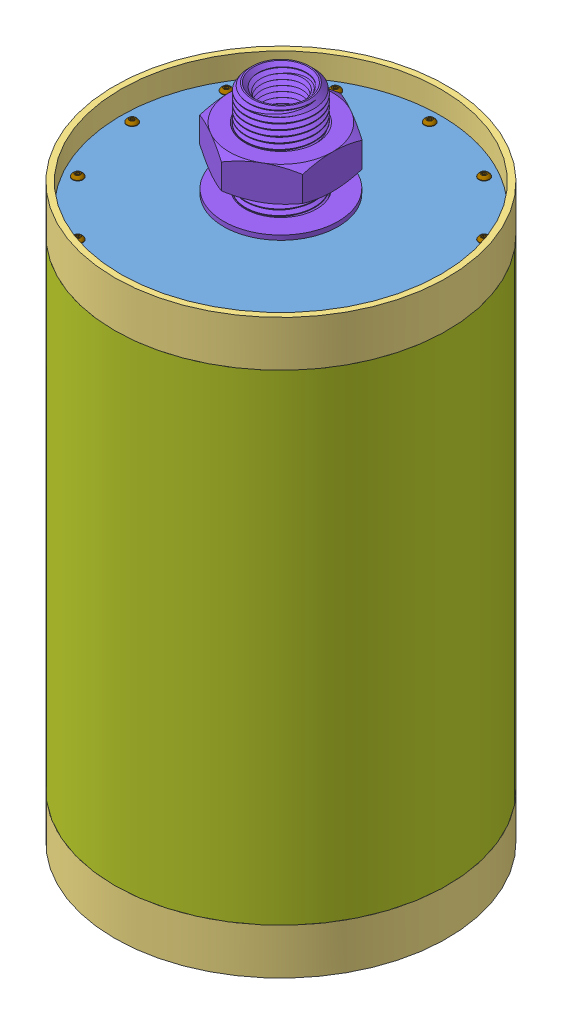
SolidWorks assembly Cryo Tank, configuration Default. Lengths in mm.
Overall size (92.25 182.79 92.25).
59 component instances, 10 part files, 35 mates.
Components (placement in the parent):
- End Cap-1: End Cap [Default] at origin size (88.9 3.17 88.9)
- Liner-1: Liner [Default] at (0 -4.7625 0) size (77.77 133.35 77.77)
- Main Ring-1: Main Ring [Default] at (0 -1.5875 0) size (92.25 25.4 92.25)
- Ring Seal-1: Ring Seal [Default] at (0 -1.5875 0) size (88.9 1.59 88.9)
- Main Ring-2: Main Ring [Default] at (0 -141.2875 0) x (-1 0 0) z (0 0 1) size (92.25 25.4 92.25)
- Ring Seal-2: Ring Seal [Default] at (0 -142.875 0) size (88.9 1.59 88.9)
- End Cap-2: End Cap [Default] at (0 -142.875 0) x (-1 0 0) z (0 0 1) size (88.9 3.17 88.9)
- 90273A015_ZINC-PLATED STL FLAT HEAD PHIL MACHINE SCREW-1: 90273A015_ZINC-PLATED STL FLAT HEAD PHIL MACHINE SCREW [90273A015] at (-35.7452 0.6985 20.6375) x (1 0 0) z (0 1 0) size (2.84 2.84 8.46) (hidden)
- 90273A015_ZINC-PLATED STL FLAT HEAD PHIL MACHINE SCREW-2: 90273A015_ZINC-PLATED STL FLAT HEAD PHIL MACHINE SCREW [90273A015] at (-41.275 0.6985 0) x (0.866025 0 0.5) z (0 1 0) size (2.84 2.84 8.46) (hidden)
- 90273A015_ZINC-PLATED STL FLAT HEAD PHIL MACHINE SCREW-3: 90273A015_ZINC-PLATED STL FLAT HEAD PHIL MACHINE SCREW [90273A015] at (-35.7452 0.6985 -20.6375) x (0.5 0 0.866025) z (0 1 0) size (2.84 2.84 8.46) (hidden)
- 90273A015_ZINC-PLATED STL FLAT HEAD PHIL MACHINE SCREW-4: 90273A015_ZINC-PLATED STL FLAT HEAD PHIL MACHINE SCREW [90273A015] at (-20.6375 0.6985 -35.7452) x (0 0 1) z (0 1 0) size (2.84 2.84 8.46) (hidden)
- 90273A015_ZINC-PLATED STL FLAT HEAD PHIL MACHINE SCREW-5: 90273A015_ZINC-PLATED STL FLAT HEAD PHIL MACHINE SCREW [90273A015] at (0 0.6985 -41.275) x (-0.5 0 0.866025) z (0 1 0) size (2.84 2.84 8.46) (hidden)
- 90273A015_ZINC-PLATED STL FLAT HEAD PHIL MACHINE SCREW-6: 90273A015_ZINC-PLATED STL FLAT HEAD PHIL MACHINE SCREW [90273A015] at (20.6375 0.6985 -35.7452) x (-0.866025 0 0.5) z (0 1 0) size (2.84 2.84 8.46) (hidden)
- 90273A015_ZINC-PLATED STL FLAT HEAD PHIL MACHINE SCREW-7: 90273A015_ZINC-PLATED STL FLAT HEAD PHIL MACHINE SCREW [90273A015] at (35.7452 0.6985 -20.6375) x (-1 0 0) z (0 1 0) size (2.84 2.84 8.46) (hidden)
- 90273A015_ZINC-PLATED STL FLAT HEAD PHIL MACHINE SCREW-8: 90273A015_ZINC-PLATED STL FLAT HEAD PHIL MACHINE SCREW [90273A015] at (41.275 0.6985 0) x (-0.866025 0 -0.5) z (0 1 0) size (2.84 2.84 8.46) (hidden)
- 90273A015_ZINC-PLATED STL FLAT HEAD PHIL MACHINE SCREW-9: 90273A015_ZINC-PLATED STL FLAT HEAD PHIL MACHINE SCREW [90273A015] at (35.7452 0.6985 20.6375) x (-0.5 0 -0.866025) z (0 1 0) size (2.84 2.84 8.46) (hidden)
- 90273A015_ZINC-PLATED STL FLAT HEAD PHIL MACHINE SCREW-10: 90273A015_ZINC-PLATED STL FLAT HEAD PHIL MACHINE SCREW [90273A015] at (20.6375 0.6985 35.7452) x (0 0 -1) z (0 1 0) size (2.84 2.84 8.46) (hidden)
- 90273A015_ZINC-PLATED STL FLAT HEAD PHIL MACHINE SCREW-11: 90273A015_ZINC-PLATED STL FLAT HEAD PHIL MACHINE SCREW [90273A015] at (0 0.6985 41.275) x (0.5 0 -0.866025) z (0 1 0) size (2.84 2.84 8.46) (hidden)
- 90273A015_ZINC-PLATED STL FLAT HEAD PHIL MACHINE SCREW-12: 90273A015_ZINC-PLATED STL FLAT HEAD PHIL MACHINE SCREW [90273A015] at (-20.6375 0.6985 35.7452) x (0.866025 0 -0.5) z (0 1 0) size (2.84 2.84 8.46) (hidden)
- 90273A015_ZINC-PLATED STL FLAT HEAD PHIL MACHINE SCREW-13: 90273A015_ZINC-PLATED STL FLAT HEAD PHIL MACHINE SCREW [90273A015] at (0 -143.5735 41.275) x (1 0 0) z (0 -1 0) size (2.84 2.84 8.46) (hidden)
- 90273A015_ZINC-PLATED STL FLAT HEAD PHIL MACHINE SCREW-25: 90273A015_ZINC-PLATED STL FLAT HEAD PHIL MACHINE SCREW [90273A015] at (-20.6375 -143.5735 35.7452) x (0.866025 0 0.5) z (0 -1 0) size (2.84 2.84 8.46) (hidden)
- 90273A015_ZINC-PLATED STL FLAT HEAD PHIL MACHINE SCREW-26: 90273A015_ZINC-PLATED STL FLAT HEAD PHIL MACHINE SCREW [90273A015] at (-35.7452 -143.5735 20.6375) x (0.5 0 0.866025) z (0 -1 0) size (2.84 2.84 8.46) (hidden)
- 90273A015_ZINC-PLATED STL FLAT HEAD PHIL MACHINE SCREW-27: 90273A015_ZINC-PLATED STL FLAT HEAD PHIL MACHINE SCREW [90273A015] at (-41.275 -143.5735 0) x (0 0 1) z (0 -1 0) size (2.84 2.84 8.46) (hidden)
- 90273A015_ZINC-PLATED STL FLAT HEAD PHIL MACHINE SCREW-28: 90273A015_ZINC-PLATED STL FLAT HEAD PHIL MACHINE SCREW [90273A015] at (-35.7452 -143.5735 -20.6375) x (-0.5 0 0.866025) z (0 -1 0) size (2.84 2.84 8.46) (hidden)
- 90273A015_ZINC-PLATED STL FLAT HEAD PHIL MACHINE SCREW-29: 90273A015_ZINC-PLATED STL FLAT HEAD PHIL MACHINE SCREW [90273A015] at (-20.6375 -143.5735 -35.7452) x (-0.866025 0 0.5) z (0 -1 0) size (2.84 2.84 8.46) (hidden)
- 90273A015_ZINC-PLATED STL FLAT HEAD PHIL MACHINE SCREW-30: 90273A015_ZINC-PLATED STL FLAT HEAD PHIL MACHINE SCREW [90273A015] at (0 -143.5735 -41.275) x (-1 0 0) z (0 -1 0) size (2.84 2.84 8.46) (hidden)
- 90273A015_ZINC-PLATED STL FLAT HEAD PHIL MACHINE SCREW-31: 90273A015_ZINC-PLATED STL FLAT HEAD PHIL MACHINE SCREW [90273A015] at (20.6375 -143.5735 -35.7452) x (-0.866025 0 -0.5) z (0 -1 0) size (2.84 2.84 8.46) (hidden)
- 90273A015_ZINC-PLATED STL FLAT HEAD PHIL MACHINE SCREW-32: 90273A015_ZINC-PLATED STL FLAT HEAD PHIL MACHINE SCREW [90273A015] at (35.7452 -143.5735 -20.6375) x (-0.5 0 -0.866025) z (0 -1 0) size (2.84 2.84 8.46) (hidden)
- 90273A015_ZINC-PLATED STL FLAT HEAD PHIL MACHINE SCREW-33: 90273A015_ZINC-PLATED STL FLAT HEAD PHIL MACHINE SCREW [90273A015] at (41.275 -143.5735 0) x (0 0 -1) z (0 -1 0) size (2.84 2.84 8.46) (hidden)
- 90273A015_ZINC-PLATED STL FLAT HEAD PHIL MACHINE SCREW-34: 90273A015_ZINC-PLATED STL FLAT HEAD PHIL MACHINE SCREW [90273A015] at (35.7452 -143.5735 20.6375) x (0.5 0 -0.866025) z (0 -1 0) size (2.84 2.84 8.46) (hidden)
- 90273A015_ZINC-PLATED STL FLAT HEAD PHIL MACHINE SCREW-35: 90273A015_ZINC-PLATED STL FLAT HEAD PHIL MACHINE SCREW [90273A015] at (20.6375 -143.5735 35.7452) x (0.866025 0 -0.5) z (0 -1 0) size (2.84 2.84 8.46) (hidden)
- CF Inner Layer-1: CF Inner Layer [Default] at (0 64.2407 0) size (79.04 133.35 79.04)
- Honeycomb Core-1: Honeycomb Core [Default] at (0 -50.3801 0) size (91.74 133.35 91.74)
- CF Outer Layer-1: CF Outer Layer [Default] at (0 15.1434 0) size (92.25 133.35 92.25)
- 50785K273_MED-PRESSURE BRASS THREADED PIPE FITTING-1: 50785K273_MED-PRESSURE BRASS THREADED PIPE FITTING [50785K273] at (0 12.7 0) x (1 0 0) z (0 -1 0) size (31.75 33 38.33)
- 98164A422_TYPE 316 SS BUTTON-HEAD SOCKET CAP SCREW-1: 98164A422_TYPE 316 SS BUTTON-HEAD SOCKET CAP SCREW [98164A422] at (-35.7452 2.4003 20.6375) x (1 0 0) z (0 1 0) size (2.9 2.9 7.34)
- 98164A422_TYPE 316 SS BUTTON-HEAD SOCKET CAP SCREW-2: 98164A422_TYPE 316 SS BUTTON-HEAD SOCKET CAP SCREW [98164A422] at (-41.275 2.4003 0) x (0.866025 0 0.5) z (0 1 0) size (2.9 2.9 7.34)
- 98164A422_TYPE 316 SS BUTTON-HEAD SOCKET CAP SCREW-3: 98164A422_TYPE 316 SS BUTTON-HEAD SOCKET CAP SCREW [98164A422] at (-35.7452 2.4003 -20.6375) x (0.5 0 0.866025) z (0 1 0) size (2.9 2.9 7.34)
- 98164A422_TYPE 316 SS BUTTON-HEAD SOCKET CAP SCREW-4: 98164A422_TYPE 316 SS BUTTON-HEAD SOCKET CAP SCREW [98164A422] at (-20.6375 2.4003 -35.7452) x (0 0 1) z (0 1 0) size (2.9 2.9 7.34)
- 98164A422_TYPE 316 SS BUTTON-HEAD SOCKET CAP SCREW-5: 98164A422_TYPE 316 SS BUTTON-HEAD SOCKET CAP SCREW [98164A422] at (0 2.4003 -41.275) x (-0.5 0 0.866025) z (0 1 0) size (2.9 2.9 7.34)
- 98164A422_TYPE 316 SS BUTTON-HEAD SOCKET CAP SCREW-6: 98164A422_TYPE 316 SS BUTTON-HEAD SOCKET CAP SCREW [98164A422] at (20.6375 2.4003 -35.7452) x (-0.866025 0 0.5) z (0 1 0) size (2.9 2.9 7.34)
- 98164A422_TYPE 316 SS BUTTON-HEAD SOCKET CAP SCREW-7: 98164A422_TYPE 316 SS BUTTON-HEAD SOCKET CAP SCREW [98164A422] at (35.7452 2.4003 -20.6375) x (-1 0 0) z (0 1 0) size (2.9 2.9 7.34)
- 98164A422_TYPE 316 SS BUTTON-HEAD SOCKET CAP SCREW-8: 98164A422_TYPE 316 SS BUTTON-HEAD SOCKET CAP SCREW [98164A422] at (41.275 2.4003 0) x (-0.866025 0 -0.5) z (0 1 0) size (2.9 2.9 7.34)
- 98164A422_TYPE 316 SS BUTTON-HEAD SOCKET CAP SCREW-9: 98164A422_TYPE 316 SS BUTTON-HEAD SOCKET CAP SCREW [98164A422] at (35.7452 2.4003 20.6375) x (-0.5 0 -0.866025) z (0 1 0) size (2.9 2.9 7.34)
- 98164A422_TYPE 316 SS BUTTON-HEAD SOCKET CAP SCREW-10: 98164A422_TYPE 316 SS BUTTON-HEAD SOCKET CAP SCREW [98164A422] at (20.6375 2.4003 35.7452) x (0 0 -1) z (0 1 0) size (2.9 2.9 7.34)
- 98164A422_TYPE 316 SS BUTTON-HEAD SOCKET CAP SCREW-11: 98164A422_TYPE 316 SS BUTTON-HEAD SOCKET CAP SCREW [98164A422] at (0 2.4003 41.275) x (0.5 0 -0.866025) z (0 1 0) size (2.9 2.9 7.34)
- 98164A422_TYPE 316 SS BUTTON-HEAD SOCKET CAP SCREW-12: 98164A422_TYPE 316 SS BUTTON-HEAD SOCKET CAP SCREW [98164A422] at (-20.6375 2.4003 35.7452) x (0.866025 0 -0.5) z (0 1 0) size (2.9 2.9 7.34)
- 98164A422_TYPE 316 SS BUTTON-HEAD SOCKET CAP SCREW-13: 98164A422_TYPE 316 SS BUTTON-HEAD SOCKET CAP SCREW [98164A422] at (0 -145.2753 41.275) x (1 0 0) z (0 -1 0) size (2.9 2.9 7.34)
- 98164A422_TYPE 316 SS BUTTON-HEAD SOCKET CAP SCREW-14: 98164A422_TYPE 316 SS BUTTON-HEAD SOCKET CAP SCREW [98164A422] at (-20.6375 -145.2753 35.7452) x (0.866025 0 0.5) z (0 -1 0) size (2.9 2.9 7.34)
- 98164A422_TYPE 316 SS BUTTON-HEAD SOCKET CAP SCREW-15: 98164A422_TYPE 316 SS BUTTON-HEAD SOCKET CAP SCREW [98164A422] at (-35.7452 -145.2753 20.6375) x (0.5 0 0.866025) z (0 -1 0) size (2.9 2.9 7.34)
- 98164A422_TYPE 316 SS BUTTON-HEAD SOCKET CAP SCREW-16: 98164A422_TYPE 316 SS BUTTON-HEAD SOCKET CAP SCREW [98164A422] at (-41.275 -145.2753 0) x (0 0 1) z (0 -1 0) size (2.9 2.9 7.34)
- 98164A422_TYPE 316 SS BUTTON-HEAD SOCKET CAP SCREW-17: 98164A422_TYPE 316 SS BUTTON-HEAD SOCKET CAP SCREW [98164A422] at (-35.7452 -145.2753 -20.6375) x (-0.5 0 0.866025) z (0 -1 0) size (2.9 2.9 7.34)
- 98164A422_TYPE 316 SS BUTTON-HEAD SOCKET CAP SCREW-18: 98164A422_TYPE 316 SS BUTTON-HEAD SOCKET CAP SCREW [98164A422] at (-20.6375 -145.2753 -35.7452) x (-0.866025 0 0.5) z (0 -1 0) size (2.9 2.9 7.34)
- 98164A422_TYPE 316 SS BUTTON-HEAD SOCKET CAP SCREW-19: 98164A422_TYPE 316 SS BUTTON-HEAD SOCKET CAP SCREW [98164A422] at (0 -145.2753 -41.275) x (-1 0 0) z (0 -1 0) size (2.9 2.9 7.34)
- 98164A422_TYPE 316 SS BUTTON-HEAD SOCKET CAP SCREW-20: 98164A422_TYPE 316 SS BUTTON-HEAD SOCKET CAP SCREW [98164A422] at (20.6375 -145.2753 -35.7452) x (-0.866025 0 -0.5) z (0 -1 0) size (2.9 2.9 7.34)
- 98164A422_TYPE 316 SS BUTTON-HEAD SOCKET CAP SCREW-21: 98164A422_TYPE 316 SS BUTTON-HEAD SOCKET CAP SCREW [98164A422] at (35.7452 -145.2753 -20.6375) x (-0.5 0 -0.866025) z (0 -1 0) size (2.9 2.9 7.34)
- 98164A422_TYPE 316 SS BUTTON-HEAD SOCKET CAP SCREW-22: 98164A422_TYPE 316 SS BUTTON-HEAD SOCKET CAP SCREW [98164A422] at (41.275 -145.2753 0) x (0 0 -1) z (0 -1 0) size (2.9 2.9 7.34)
- 98164A422_TYPE 316 SS BUTTON-HEAD SOCKET CAP SCREW-23: 98164A422_TYPE 316 SS BUTTON-HEAD SOCKET CAP SCREW [98164A422] at (35.7452 -145.2753 20.6375) x (0.5 0 -0.866025) z (0 -1 0) size (2.9 2.9 7.34)
- 98164A422_TYPE 316 SS BUTTON-HEAD SOCKET CAP SCREW-24: 98164A422_TYPE 316 SS BUTTON-HEAD SOCKET CAP SCREW [98164A422] at (20.6375 -145.2753 35.7452) x (0.866025 0 -0.5) z (0 -1 0) size (2.9 2.9 7.34)
Mates (geometry in assembly coordinates):
- Coincident13: coincident: point of Liner-1; point of assembly
- Coincident14: coincident aligned: plane of Liner-1 through (0 -4.7625 0) normal (0 0 1); plane of assembly through (0 0 0) normal (0 0 1)
- Coincident15: coincident aligned: plane of End Cap-1 through (0 0 0) normal (0 0 1); plane of assembly through (0 0 0) normal (0 0 1)
- Coincident16: coordinate: point of End Cap-1; point of assembly
- Coincident17: coincident anti-aligned: line of ? through (110 0 53.4125) axis (0 0 -1)
- Coincident18: coincident aligned: plane of Ring Seal-1 through (0 -1.5875 0) normal (0 0 1); plane of assembly through (0 0 0) normal (0 0 1)
- Coincident20: coincident anti-aligned: line of ? through (110 0 53.4125) axis (0 0 -1)
- Coincident21: coincident aligned: plane of Main Ring-1 through (0 -1.5875 0) normal (0 0 1); plane of assembly through (0 0 0) normal (0 0 1)
- Coincident22: coincident: unknown of ?
- Coincident23: coincident anti-aligned: line of Ring Seal-2 through (110 0 -87.875) axis (0 0 -1); line of assembly
- Coincident24: coincident aligned: plane of Ring Seal-2 through (0 -142.875 0) normal (0 0 1); plane of assembly through (0 0 0) normal (0 0 1)
- Coincident25: coincident: point of Ring Seal-2; point of assembly
- Coincident26: coincident aligned: line of End Cap-2 through (110 0 -197.875) axis (0 0 1); line of assembly
- Coincident27: coincident aligned: plane of End Cap-2 through (0 -142.875 0) normal (0 0 1); plane of assembly through (0 0 0) normal (0 0 1)
- Coincident28: coincident: point of End Cap-2; point of assembly
- Coincident29: coincident aligned: line of Main Ring-2 through (110 0 -196.2875) axis (0 0 1); line of assembly
- Coincident30: coincident aligned: plane of Main Ring-2 through (0 -141.2875 0) normal (0 0 1); plane of assembly through (0 0 0) normal (0 0 1)
- Coincident31: coincident: point of Main Ring-2; point of assembly
- Coincident32: coincident: unknown of ?
- Coincident33: coincident aligned: plane of End Cap-1 through (-44.45 1.5875 0) normal (0 1 0); plane of 90273A015_ZINC-PLATED STL FLAT HEAD PHIL MACHINE SCREW-1 through (-35.7452 1.5875 19.8755) normal (0 1 0)
- Concentric1: concentric anti-aligned: circle of End Cap-1; circle of 90273A015_ZINC-PLATED STL FLAT HEAD PHIL MACHINE SCREW-1
- Concentric2: concentric anti-aligned: circle of End Cap-2; circle of 90273A015_ZINC-PLATED STL FLAT HEAD PHIL MACHINE SCREW-13
- Coincident34: coincident aligned: plane of End Cap-2 through (44.45 -144.4625 0) normal (0 -1 0); plane of 90273A015_ZINC-PLATED STL FLAT HEAD PHIL MACHINE SCREW-13 through (0 -144.4625 42.037) normal (0 -1 0)
- Coincident35: coincident aligned: line of Main Ring-1 through (110 0 53.4125) axis (0 0 -1); line of CF Inner Layer-1 through (110 0 119.2407) axis (0 0 -1)
- Coincident36: coincident aligned: plane of CF Inner Layer-1 through (0 64.2407 0) normal (0 0 1); plane of assembly through (0 0 0) normal (0 0 1)
- Coincident37: coincident aligned: line of CF Inner Layer-1 through (110 0 119.2407) axis (0 0 -1); line of Honeycomb Core-1 through (110 0 4.6199) axis (0 0 -1)
- Coincident38: coincident aligned: plane of Honeycomb Core-1 through (0 -50.3801 0) normal (0 0 1); plane of assembly through (0 0 0) normal (0 0 1)
- Coincident39: coincident aligned: line of CF Inner Layer-1 through (110 0 119.2407) axis (0 0 -1); line of CF Outer Layer-1 through (110 0 70.1434) axis (0 0 -1)
- Coincident40: coincident aligned: plane of CF Outer Layer-1 through (0 15.1434 0) normal (0 0 1); plane of assembly through (0 0 0) normal (0 0 1)
- Concentric3: concentric aligned: cylinder of End Cap-1 through (0 55 0) axis (0 1 0) radius 9.525; cylinder of 50785K273_MED-PRESSURE BRASS THREADED PIPE FITTING-1 through (0 -6.35 0) axis (0 1 0) radius 5.5563
- Coincident41: coincident anti-aligned: plane of End Cap-1 through (-44.45 0 0) normal (0 -1 0); plane of 50785K273_MED-PRESSURE BRASS THREADED PIPE FITTING-1 through (0 0 14.6647) normal (0 1 0)
- Concentric4: concentric aligned: cylinder of End Cap-1 through (-35.7452 1.5875 20.6375) axis (0 1 0) radius 0.7937; cylinder of 98164A422_TYPE 316 SS BUTTON-HEAD SOCKET CAP SCREW-1 through (-35.7452 2.4003 20.6375) axis (0 1 0) radius 1.4478
- Coincident42: coincident anti-aligned: plane of End Cap-1 through (-44.45 1.5875 0) normal (0 1 0); plane of 98164A422_TYPE 316 SS BUTTON-HEAD SOCKET CAP SCREW-1 through (-35.7452 1.5875 22.0853) normal (0 -1 0)
- Concentric5: concentric aligned: cylinder of End Cap-2 through (0 -144.4625 41.275) axis (0 -1 0) radius 0.7937; cylinder of 98164A422_TYPE 316 SS BUTTON-HEAD SOCKET CAP SCREW-13 through (0 -145.2753 41.275) axis (0 -1 0) radius 1.4478
- Coincident43: coincident anti-aligned: plane of End Cap-2 through (44.45 -144.4625 0) normal (0 -1 0); plane of 98164A422_TYPE 316 SS BUTTON-HEAD SOCKET CAP SCREW-13 through (0 -144.4625 39.8272) normal (0 1 0)
